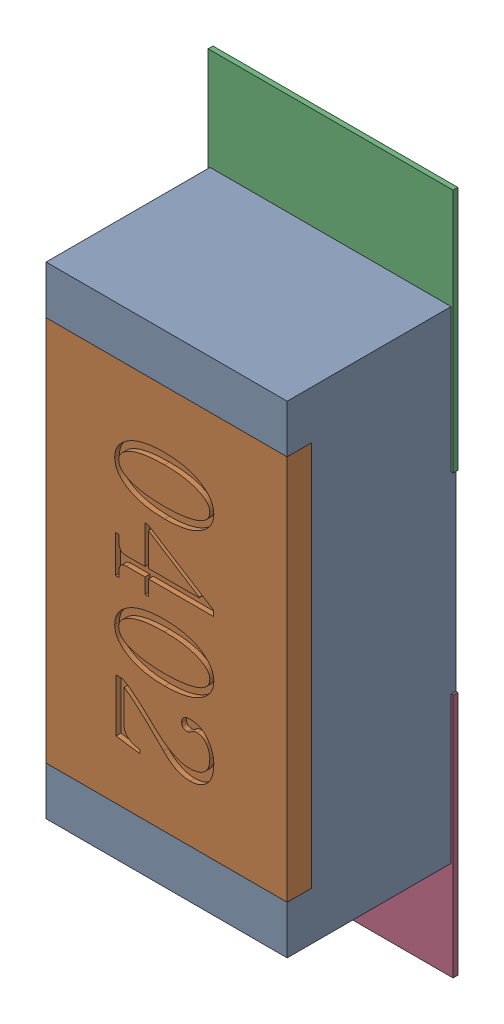
SolidWorks assembly R61, configuration Défaut. Lengths in mm.
Overall size (0.51 1.42 0.35).
5 component instances, 2 part files, 0 mates.
Components (placement in the parent):
- R0402-1: R0402 [Défaut] at (34.3025 -32.3342 0) x (0 -1 0) z (0 0 1) size (1 0.5 0.35)
- 6504207776-1: 6504207776 [Défaut] at (34.3026 -31.8771 0) size (0.51 0.51 0.01)
  - Extruded-1: Extruded [Défaut] at origin size (0.51 0.51 0.01)
- 6504207776-2: 6504207776 [Défaut] at (34.3026 -32.7842 0) size (0.51 0.51 0.01)
  - Extruded-1: Extruded [Défaut] at origin size (0.51 0.51 0.01)
